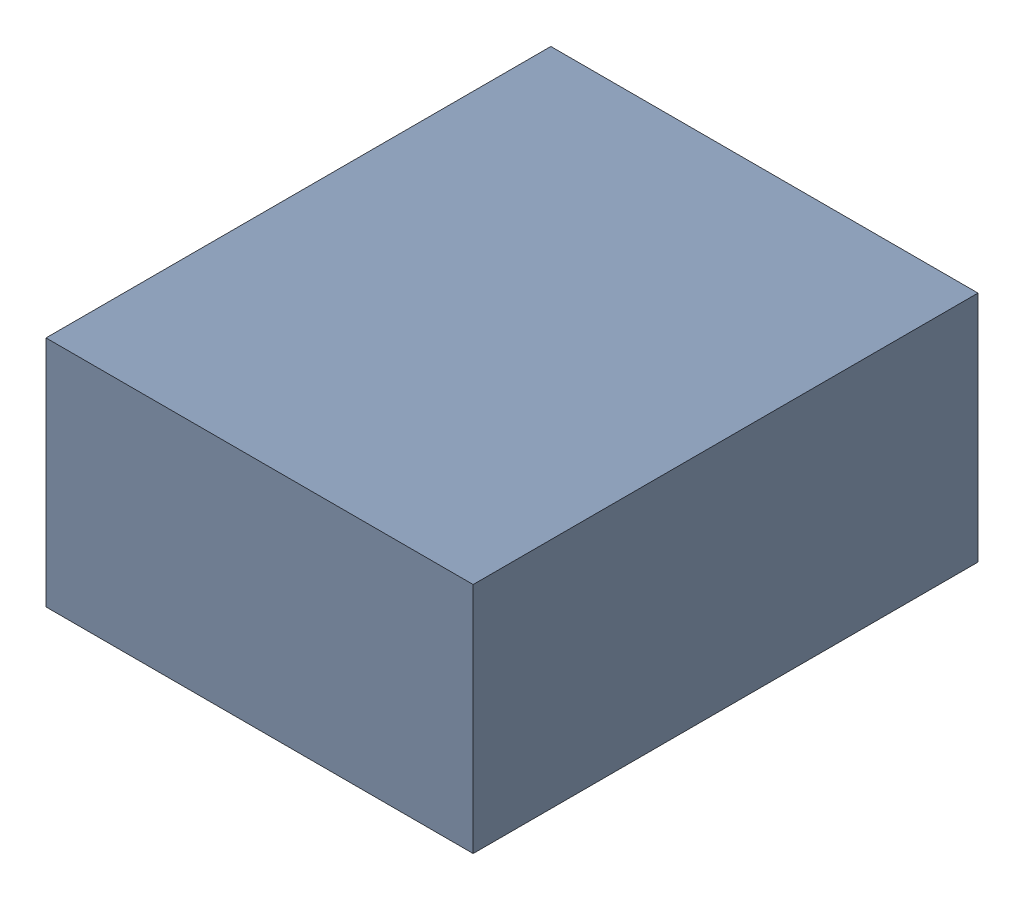
SolidWorks assembly C26_TDA4, configuration Standard. Lengths in mm.
Overall size (1.1 0.6 1.3).
2 component instances, 1 part files, 0 mates.
Components (placement in the parent):
- 885542240-1: 885542240 [Standard] at (0.38 -39.99 0) size (1.1 0.6 1.3)
  - Extruded_28-1: Extruded_28 [Standard] at origin size (1.1 0.6 1.3)
